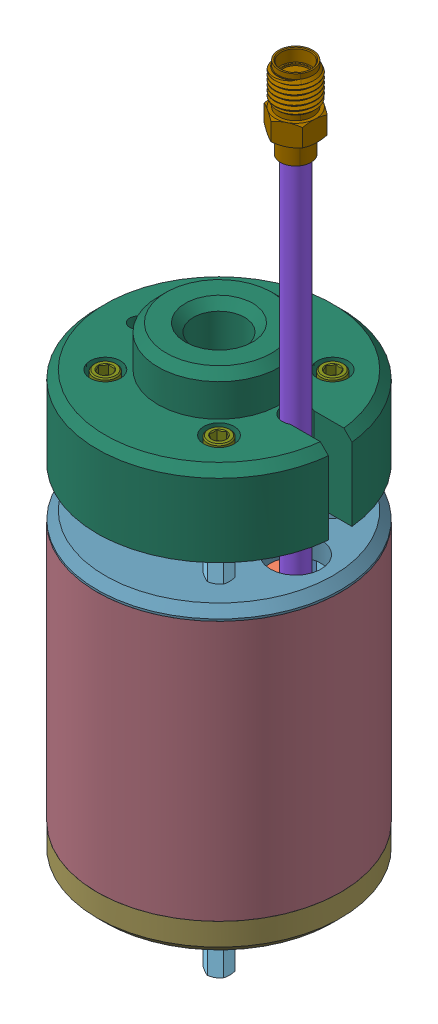
SolidWorks assembly 122001559, configuration Default. Lengths in mm.
Overall size (38.1 120.49 38.1).
53 component instances, 16 part files, 17 mates.
Components (placement in the parent):
- 122001556-1: 122001556 [Default] at origin size (32.96 115.97 31.75)
  - 122001547-1: 122001547 [Default] at origin size (32.96 115.97 31.75)
    - 121003116-1: 121003116 [Default] at origin size (31.75 1.6 31.75)
    - 121003116-4: 121003116 [Default] at (0 -1.6 0) size (31.75 1.6 31.75)
    - 121003116-7: 121003116 [Default] at (0 -3.2 0) size (31.75 1.6 31.75)
    - 121003117-1: 121003117 [Default] at (0 11.15 0) size (31.75 1.63 31.75)
    - 121003118-1: 121003118 [Default] at (0 -11.15 0) size (31.75 1.63 31.75)
    - 92511A129-1: 92511A129 [92511A129] at (8.89 7.175 -8.89) x (0.864839 0 -0.502049) z (0 -1 0) size (3.17 3.17 6.35)
    - 91780A023-1: 91780A023 [91780A023] at (8.89 -15.125 8.89) x (1 0 0) z (0 -1 0) size (3.17 3.67 6.66)
    - 91780A023-2: 91780A023 [91780A023] at (-8.89 -15.125 8.89) x (0 0 1) z (0 -1 0) size (3.17 3.67 6.66)
    - 91780A023-3: 91780A023 [91780A023] at (-8.89 -15.125 -8.89) x (-1 0 0) z (0 -1 0) size (3.17 3.67 6.66)
    - 91780A023-4: 91780A023 [91780A023] at (8.89 -15.125 -8.89) x (0 0 -1) z (0 -1 0) size (3.17 3.67 6.66)
    - 93225A413-1: 93225A413 [93225A413] at (8.89 0.75 8.89) x (0 -1 0) z (0 0 1) size (51.63 2.21 2.52)
    - 93225A413-2: 93225A413 [93225A413] at (-8.89 0.75 8.89) x (0 -1 0) z (-1 0 0) size (51.63 2.21 2.52)
    - 93225A413-3: 93225A413 [93225A413] at (-8.89 0.75 -8.89) x (0 -1 0) z (0 0 -1) size (51.63 2.21 2.52)
    - 93225A413-4: 93225A413 [93225A413] at (8.89 0.75 -8.89) x (0 -1 0) z (1 0 0) size (51.63 2.21 2.52)
    - 122001546-1: 122001546 [Default] at (12 5 0) x (0 0 -1) z (1 0 0) size (10.16 86.37 12.68)
      - 121003119-1: 121003119 [Default] at origin size (7.2 0.85 10.2)
      - 121003122-1: 121003122 [Default] at (0 0.8254 0) x (0.731519 0 0.681822) z (-0.681822 0 0.731519) size (3.58 77.47 3.58)
      - 901-9704-1: 901-9704 [Default] at (0 73.2154 0) x (0 1 0) z (-0.546944 0 0.837169) size (12.71 7.34 7.34)
    - 121003116-10: 121003116 [Default] at (0 1.6 0) size (31.75 1.6 31.75)
    - 121003116-11: 121003116 [Default] at (0 3.2 0) size (31.75 1.6 31.75)
    - 92511A129-9: 92511A129 [92511A129] at (8.89 7.175 8.89) x (0.502049 0 0.864839) z (0 -1 0) size (3.17 3.17 6.35)
    - 92511A129-10: 92511A129 [92511A129] at (-8.89 7.175 8.89) x (-0.864839 0 0.502049) z (0 -1 0) size (3.17 3.17 6.35)
    - 92511A129-11: 92511A129 [92511A129] at (-8.89 7.175 -8.89) x (-0.502049 0 -0.864839) z (0 -1 0) size (3.17 3.17 6.35)
    - 92511A129-12: 92511A129 [92511A129] at (8.89 -7.175 -8.89) x (0.864839 0 -0.502049) z (0 -1 0) size (3.17 3.17 6.35)
    - 92511A129-13: 92511A129 [92511A129] at (-8.89 -7.175 -8.89) x (-0.502049 0 -0.864839) z (0 -1 0) size (3.17 3.17 6.35)
    - 92511A129-14: 92511A129 [92511A129] at (8.89 -7.175 8.89) x (0.502049 0 0.864839) z (0 -1 0) size (3.17 3.17 6.35)
    - 92511A129-15: 92511A129 [92511A129] at (-8.89 -7.175 8.89) x (-0.864839 0 0.502049) z (0 -1 0) size (3.17 3.17 6.35)
    - 91780A023-5: 91780A023 [91780A023] at (8.89 15.125 8.89) x (1 0 0) z (0 1 0) size (3.17 3.67 6.66)
    - 91780A023-6: 91780A023 [91780A023] at (-8.89 15.125 -8.89) x (-1 0 0) z (0 1 0) size (3.17 3.67 6.66)
    - 91780A023-7: 91780A023 [91780A023] at (8.89 15.125 -8.89) x (0 0 1) z (0 1 0) size (3.17 3.67 6.66)
    - 91780A023-8: 91780A023 [91780A023] at (-8.89 15.125 8.89) x (0 0 -1) z (0 1 0) size (3.17 3.67 6.66)
  - 121003138-1: 121003138 [Default] at (-6.35 -0.115 0) x (0 0 -1) z (1 0 0) size (25.4 27.94 3.17)
  - 121003139-1: 121003139 [COUPLING LOOP SIDE] at (0 4 0) x (0 0 -1) z (1 0 0) size (21.06 6.35 21.06)
  - 121003139-2: 121003139 [Default] at (0 -10.35 0) size (21.06 6.35 21.06)
  - 121003138-2: 121003138 [Default] at (3.175 -0.115 0) x (0 0 -1) z (1 0 0) size (25.4 27.94 3.17)
- 121003143-1: 121003143 [3D PRINTED] at (0 -23.0625 0) size (38.1 4.76 38.1)
- 91780A023-1: 91780A023 [91780A023] at (-8.89 -26.2375 -8.89) x (1 0 0) z (0 -1 0) size (3.17 3.67 6.66)
- 91780A023-2: 91780A023 [91780A023] at (8.89 -26.2375 -8.89) x (0 0 1) z (0 -1 0) size (3.17 3.67 6.66)
- 91780A023-3: 91780A023 [91780A023] at (8.89 -26.2375 8.89) x (-1 0 0) z (0 -1 0) size (3.17 3.67 6.66)
- 91780A023-4: 91780A023 [91780A023] at (-8.89 -26.2375 8.89) x (0 0 -1) z (0 -1 0) size (3.17 3.67 6.66)
- 121003107-1: 121003107 [3D PRINTED] at (0 -18.3 0) size (38.1 40.64 38.1)
- 121003108-1: 121003108 [3D PRINTED] at (0 20.7525 0) size (38.1 3.17 38.1)
- 91780A023-5: 91780A023 [91780A023] at (-8.89 27.1025 -8.89) x (-1 0 0) z (0 1 0) size (3.17 3.67 6.66)
- 91780A023-6: 91780A023 [91780A023] at (-8.89 27.1025 8.89) x (0 0 1) z (0 1 0) size (3.17 3.67 6.66)
- 91780A023-7: 91780A023 [91780A023] at (8.89 27.1025 8.89) x (1 0 0) z (0 1 0) size (3.17 3.67 6.66)
- 91780A023-8: 91780A023 [91780A023] at (8.89 27.1025 -8.89) x (0 0 -1) z (0 1 0) size (3.17 3.67 6.66)
- 121003110-1: 121003110 [Default] at (0 30.2775 0) size (38.01 19.05 38.1)
- 92185A083-1: 92185A083 [92185A083] at (-8.89 42.9775 8.89) x (-0.837169 0 -0.546944) z (0 1 0) size (3.57 3.57 15.2)
- 92185A083-2: 92185A083 [92185A083] at (8.89 42.9775 8.89) x (-0.546944 0 0.837169) z (0 1 0) size (3.57 3.57 15.2)
- 92185A083-3: 92185A083 [92185A083] at (8.89 42.9775 -8.89) x (0.837169 0 0.546944) z (0 1 0) size (3.57 3.57 15.2)
- 92185A083-4: 92185A083 [92185A083] at (-8.89 42.9775 -8.89) x (0.546944 0 -0.837169) z (0 1 0) size (3.57 3.57 15.2)
Mates (geometry in assembly coordinates):
- Concentric1: concentric anti-aligned: circle of 122001556-1/122001547-1/93225A413-4; cylinder of 121003143-1 through (8.89 -18.3 -8.89) axis (0 1 0) radius 1.2192
- Concentric2: concentric anti-aligned: circle of 122001556-1/122001547-1/93225A413-3; cylinder of 121003143-1 through (-8.89 -18.3 -8.89) axis (0 1 0) radius 1.2192
- Coincident1: coincident anti-aligned: plane of 122001556-1/122001547-1/91780A023-3 through (-8.89 -18.3 -10.7231) normal (0 -1 0); plane of 121003143-1 through (0 -18.3 0) normal (0 1 0)
- Concentric3: concentric anti-aligned: circle of 122001556-1/122001547-1/93225A413-3; circle of 91780A023-1
- Coincident2: coincident anti-aligned: plane of 121003143-1 through (0 -23.0625 0) normal (0 -1 0); plane of 91780A023-1 through (-8.89 -23.0625 -7.0569) normal (0 1 0)
- Concentric4: concentric aligned: cylinder of 121003143-1 through (0 -18.3 0) axis (0 -1 0) radius 19.05; cylinder of 121003107-1 through (0 22.34 0) axis (0 -1 0) radius 19.05
- Coincident3: coincident anti-aligned: plane of 121003143-1 through (0 -18.3 0) normal (0 1 0); plane of 121003107-1 through (0 -18.3 0) normal (0 -1 0)
- Concentric5: concentric aligned: circle of 122001556-1/122001547-1/93225A413-4; cylinder of 121003108-1 through (8.89 23.9275 -8.89) axis (0 1 0) radius 1.2192
- Concentric6: concentric aligned: circle of 122001556-1/122001547-1/93225A413-3; cylinder of 121003108-1 through (-8.89 23.9275 -8.89) axis (0 1 0) radius 1.2192
- Coincident4: coincident anti-aligned: plane of 121003107-1 through (0 22.34 0) normal (0 1 0); plane of 121003108-1 through (19.05 22.34 0) normal (0 -1 0)
- Concentric7: concentric anti-aligned: circle of 122001556-1/122001547-1/93225A413-3; circle of 91780A023-5
- Coincident5: coincident anti-aligned: plane of 121003108-1 through (0 23.9275 0) normal (0 1 0); plane of 91780A023-5 through (-8.89 23.9275 -7.0569) normal (0 -1 0)
- Concentric8: concentric anti-aligned: circle of 91780A023-6; cylinder of 121003110-1 through (-8.89 42.9775 8.89) axis (0 1 0) radius 1.3526
- Concentric9: concentric anti-aligned: circle of 91780A023-7; cylinder of 121003110-1 through (8.89 42.9775 8.89) axis (0 1 0) radius 1.3526
- Coincident6: coincident anti-aligned: plane of 91780A023-7 through (8.89 30.2775 7.0569) normal (0 1 0); plane of 121003110-1 through (19.05 30.2775 0) normal (0 -1 0)
- Concentric10: concentric aligned: cylinder of 121003110-1 through (-8.89 42.9775 8.89) axis (0 1 0) radius 1.3526; cylinder of 92185A083-1 through (-8.89 42.9775 8.89) axis (0 1 0) radius 1.7859
- Coincident7: coincident anti-aligned: plane of 121003110-1 through (-7.5375 40.7931 8.89) normal (0 1 0); plane of 92185A083-1 through (-8.0109 40.7931 7.5444) normal (0 -1 0)
